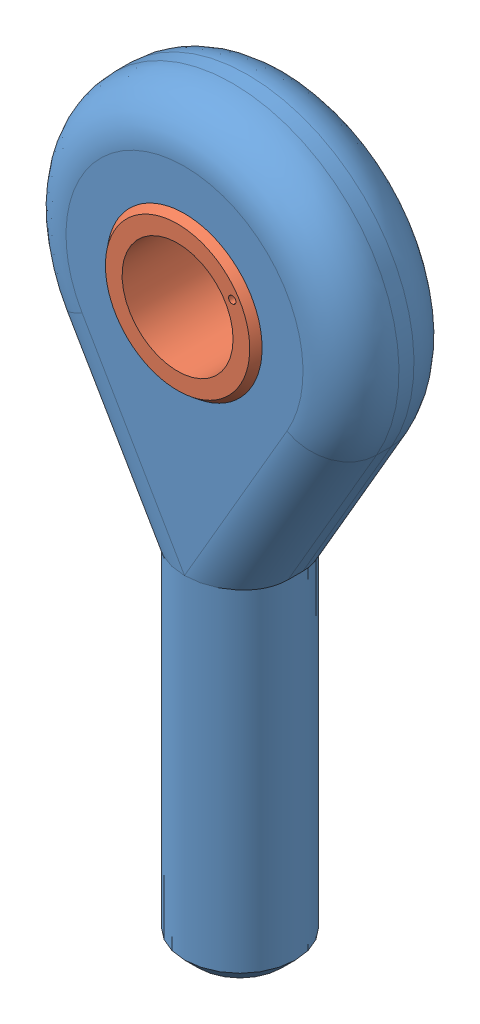
SolidWorks assembly Link Insert Assembly, configuration Default. Lengths in mm.
Overall size (24 54 13.75).
2 component instances, 2 part files, 3 mates.
Components (placement in the parent):
- Link-1: Link [Default] at (13.2343 18.3157 41.9532)
- Spherical Bearing Ball-1: Spherical Bearing Ball [Default] at (13.2343 47.8157 41.9532) x (0 0 1) z (-0.524805 0.851222 0)
Mates (geometry in assembly coordinates):
- Concentric2: concentric: sphere of Link-1; sphere of Spherical Bearing Ball-1
- LimitAngle3: limit planar angle = 0 rad aligned: plane of Spherical Bearing Ball-1 through (13.2343 47.8157 41.9532) normal (0 0 1); plane of Link-1 through (13.2343 18.3157 41.9532) normal (0 0 1)
- Tangent1: tangent aligned: sphere of Link-1; sphere of Spherical Bearing Ball-1
